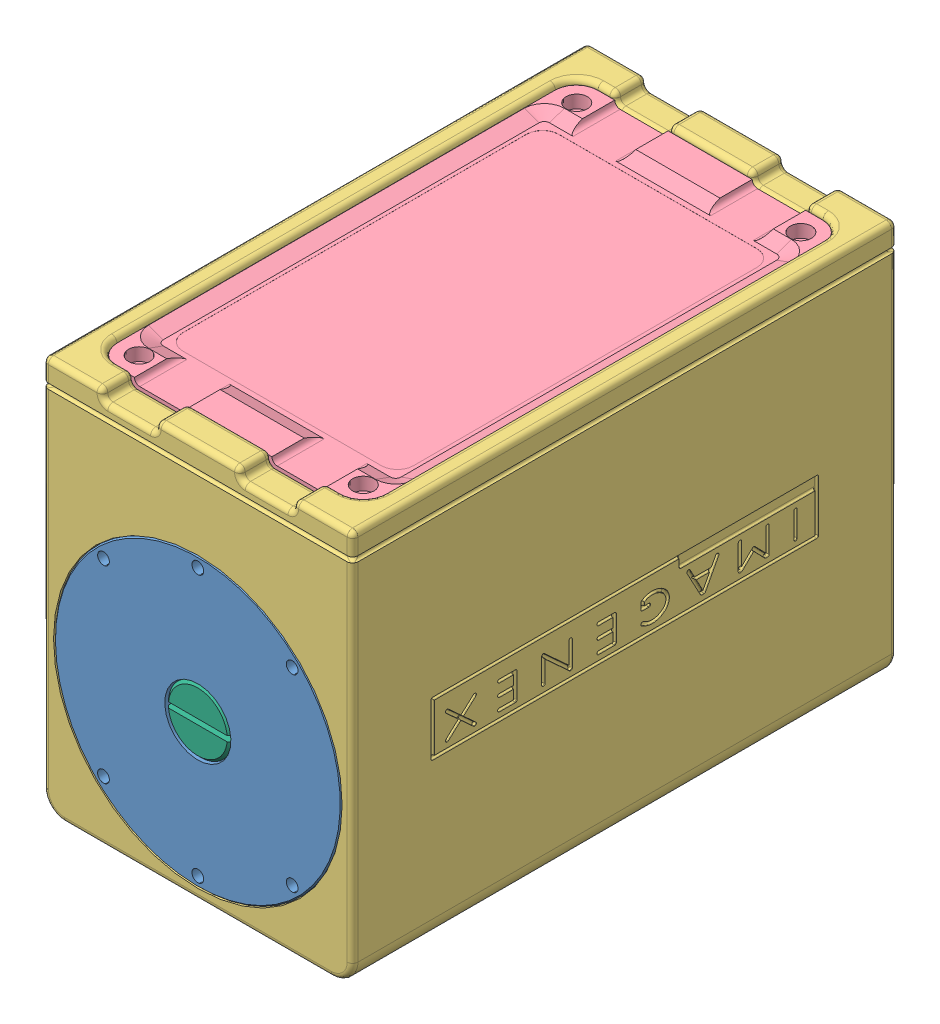
SolidWorks assembly DT100 Delrin, configuration Default. Lengths in mm.
Overall size (120.87 131.81 199.71).
7 component instances, 7 part files, 0 mates.
Components (placement in the parent):
- 325-717-01-MOD-1: 325-717-01-MOD [Default] at (31.45 -72.3392 61.4599) x (0 0 1) z (0.707107 0.707107 0) size (14.29 85.47 85.47)
- 325-717-02-1: 325-717-02 [Default] at (31.45 -72.3392 -71.8901) x (0 0 -1) z (0.707107 0.707107 0) size (15.88 85.47 85.47)
- d32571600-1: d32571600 [Default] at (77.4875 -29.5402 75.7474) size (92.08 117.41 161.93)
- d33517700-1: d33517700 [Default] at (71.2645 -29.5402 66.2224) size (79.63 26.99 142.88)
- subconnMCBH8MSS-1: subconnMCBH8MSS [Default] at (31.45 -72.3392 -87.7651) x (-0.837169 0.546944 0) z (-0.546944 -0.837169 0) size (21.88 48.89 20.68)
- 325-601-00-1: 325-601-00 [Default] at (31.45 -72.3392 63.0474) x (1 0 0) z (0 -1 0) size (19.05 12.7 19.05)
- 325-763-00-1: 325-763-00 [Default] at (6.685 -72.3392 -71.8901) x (1 0 0) z (0 1 0) size (19.05 14.29 19.05)
